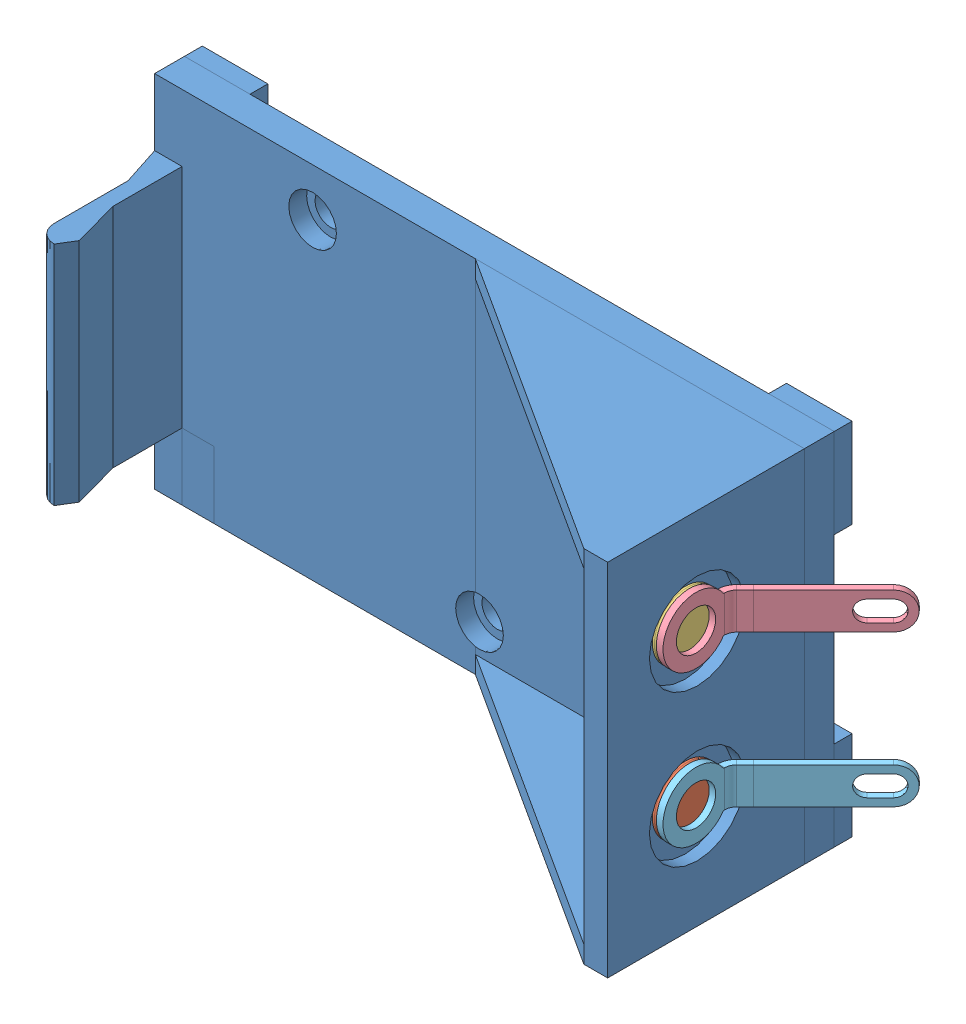
SolidWorks assembly BatteryHolder_9V_Eyelet_or_Pins, configuration Default. Lengths in mm.
Overall size (62.36 30.2 20.5).
8 component instances, 7 part files, 0 mates.
Components (placement in the parent):
- BatteryHolder_9V_Eyelet_or_Pins.step-1: BatteryHolder_9V_Eyelet_or_Pins.step [Default] at origin size (62.36 30.2 29.4)
  - Body_Housing.step-1: Body_Housing.step [Default] at origin size (54.5 30.2 20.5)
  - Body_Anode.step-1: Body_Anode.step [Default] at (22 -6.35 11.5) size (4.62 9.24 8)
  - Body_Cathode.step-1: Body_Cathode.step [Default] at (22 6.35 11.5) size (4.62 7.3 7.3)
  - Body_Pin.step-1: Body_Pin.step [Default] at origin size (0.8 0.8 19.4) (hidden)
  - Array_Pins.step-1: Array_Pins.step [Default] at origin size (0.8 13.5 19.4) (hidden)
  - Eyelet_bended_Cathode.step-1: Eyelet_bended_Cathode.step [Default] at (26.6 6.35 11.5) x (0 1 0) z (1 0 0) size (5.54 13.94 8.51)
  - Eyelet_bended_Anode.step-1: Eyelet_bended_Anode.step [Default] at (26.6 -6.35 11.5) x (0 1 0) z (1 0 0) size (5.54 13.94 8.51)
